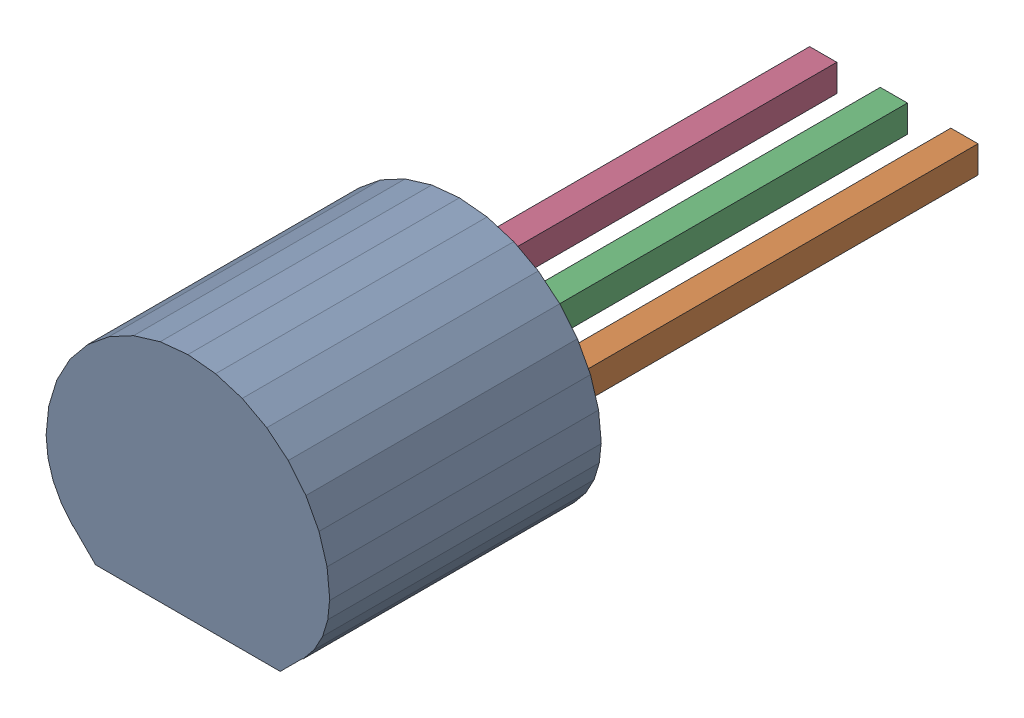
SolidWorks assembly User Library-TO-92_Str_Free-Models, configuration Default. Lengths in mm.
Overall size (5.23 4.2 13).
10 component instances, 2 part files, 0 mates.
Components (placement in the parent):
- User Library-TO-92_Str_BODY-1: User Library-TO-92_Str_BODY [Default] at origin size (5.23 4.2 5)
  - User Library-TO-92_Str_Open_CASCADE_STEP_translator_6.2_1.1-1: User Library-TO-92_Str_Open_CASCADE_STEP_translator_6.2_1.1 [Default] at origin size (5.23 4.2 5)
    - User Library-TO-92_Str_547225856-1: User Library-TO-92_Str_547225856 [Default] at (0 0.5113 5) size (5.23 4.2 5)
      - User Library-TO-92_Str_Extruded-1: User Library-TO-92_Str_Extruded [Default] at origin size (5.23 4.2 5)
- User Library-TO-92_Str_577959568-1: User Library-TO-92_Str_577959568 [Default] at (1.3 0 -3) size (0.5 0.5 8)
  - User Library-TO-92_Str_Extruded_2-1: User Library-TO-92_Str_Extruded_2 [Default] at origin size (0.5 0.5 8)
- User Library-TO-92_Str_577959568-2: User Library-TO-92_Str_577959568 [Default] at (0 0 -3) size (0.5 0.5 8)
  - User Library-TO-92_Str_Extruded_2-1: User Library-TO-92_Str_Extruded_2 [Default] at origin size (0.5 0.5 8)
- User Library-TO-92_Str_577959568-3: User Library-TO-92_Str_577959568 [Default] at (-1.3 0 -3) size (0.5 0.5 8)
  - User Library-TO-92_Str_Extruded_2-1: User Library-TO-92_Str_Extruded_2 [Default] at origin size (0.5 0.5 8)
